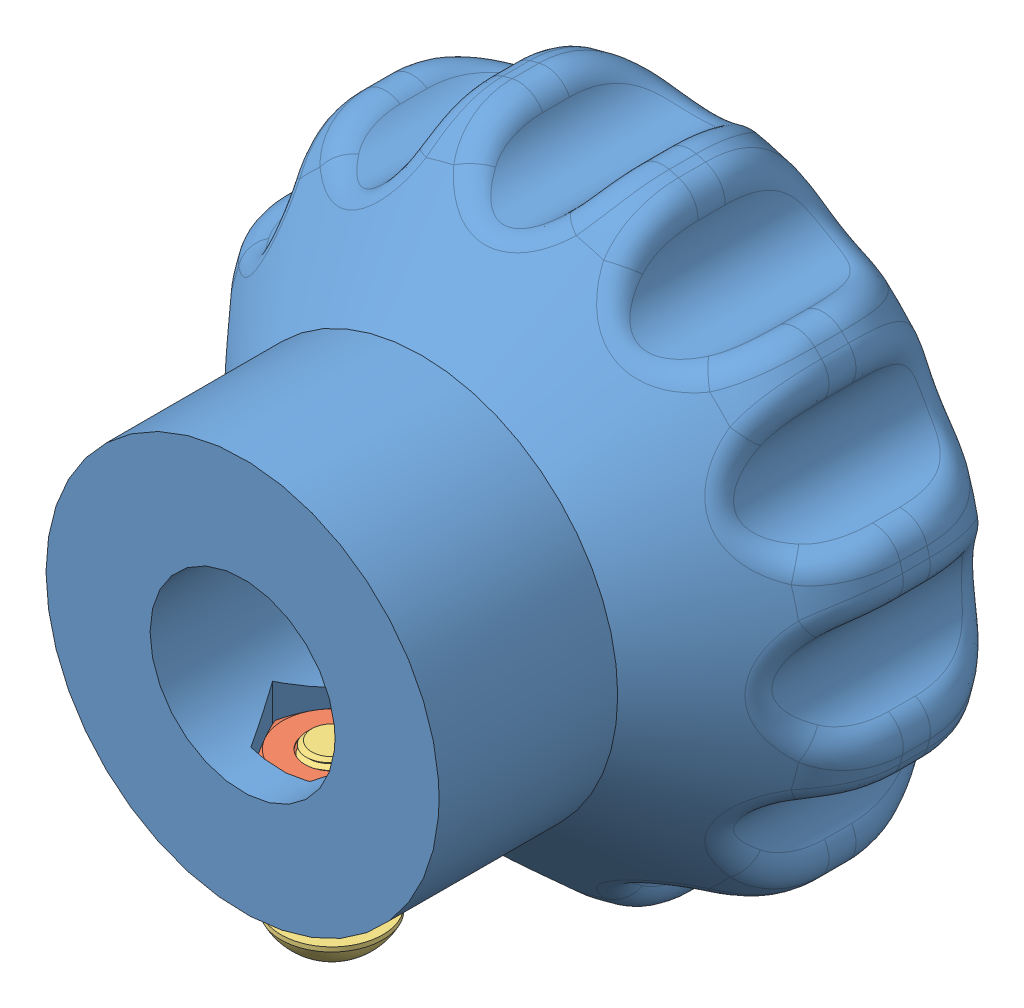
SolidWorks assembly Manual_Movement_Knob, configuration Default. Lengths in mm.
Overall size (35.58 35.58 27).
3 component instances, 3 part files, 6 mates.
Components (placement in the parent):
- Rod_End_Knob-1: Rod_End_Knob [Default] at origin size (35.58 35.58 27)
- 3mm_Hex_Nut(McMaster_90591A121)-1: 3mm_Hex_Nut(McMaster_90591A121) [90591A121] at (0 -6.8 5) x (0.866025 0 0.5) z (-0.5 0 0.866025) size (5.5 2.58 6.35)
- 3mmX8mm_Buttonhead(McMaster_94500A222)-1: 3mmX8mm_Buttonhead(McMaster_94500A222) [94500A222] at (0 -14.825 5) x (0.866025 0 -0.5) z (0 -1 0) size (5.7 5.7 9.95)
Mates (geometry in assembly coordinates):
- Concentric1: concentric anti-aligned: cylinder of Rod_End_Knob-1 through (0 -11.001 5) axis (0 1 0) radius 1.675; circle of 3mm_Hex_Nut(McMaster_90591A121)-1
- Parallel1: parallel aligned: plane of Rod_End_Knob-1 through (0 -8 2.125) normal (0 0 1); plane of 3mm_Hex_Nut(McMaster_90591A121)-1 through (-1.5877 -5.6 7.75) normal (0 0 1)
- Coincident2: coincident anti-aligned: plane of Rod_End_Knob-1 through (0 -8 0) normal (0 1 0); plane of 3mm_Hex_Nut(McMaster_90591A121)-1 through (3.1754 -8 5) normal (0 -1 0)
- Concentric3: concentric anti-aligned: cylinder of Rod_End_Knob-1 through (0 -11.001 5) axis (0 1 0) radius 1.675; cylinder of 3mmX8mm_Buttonhead(McMaster_94500A222)-1 through (0 -14.825 5) axis (0 -1 0) radius 2.85
- Parallel2: parallel aligned: plane of Rod_End_Knob-1 through (0 -8 2.125) normal (0 0 1); plane of 3mmX8mm_Buttonhead(McMaster_94500A222)-1 through (-0.5774 -13.67 4) normal (0 0 1)
- Tangent1: tangent anti-aligned: cylinder of Rod_End_Knob-1 through (0 0 10) axis (0 0 -1) radius 5.175; plane of 3mmX8mm_Buttonhead(McMaster_94500A222)-1 through (-0.75 -5.175 3.701) normal (0 1 0)
